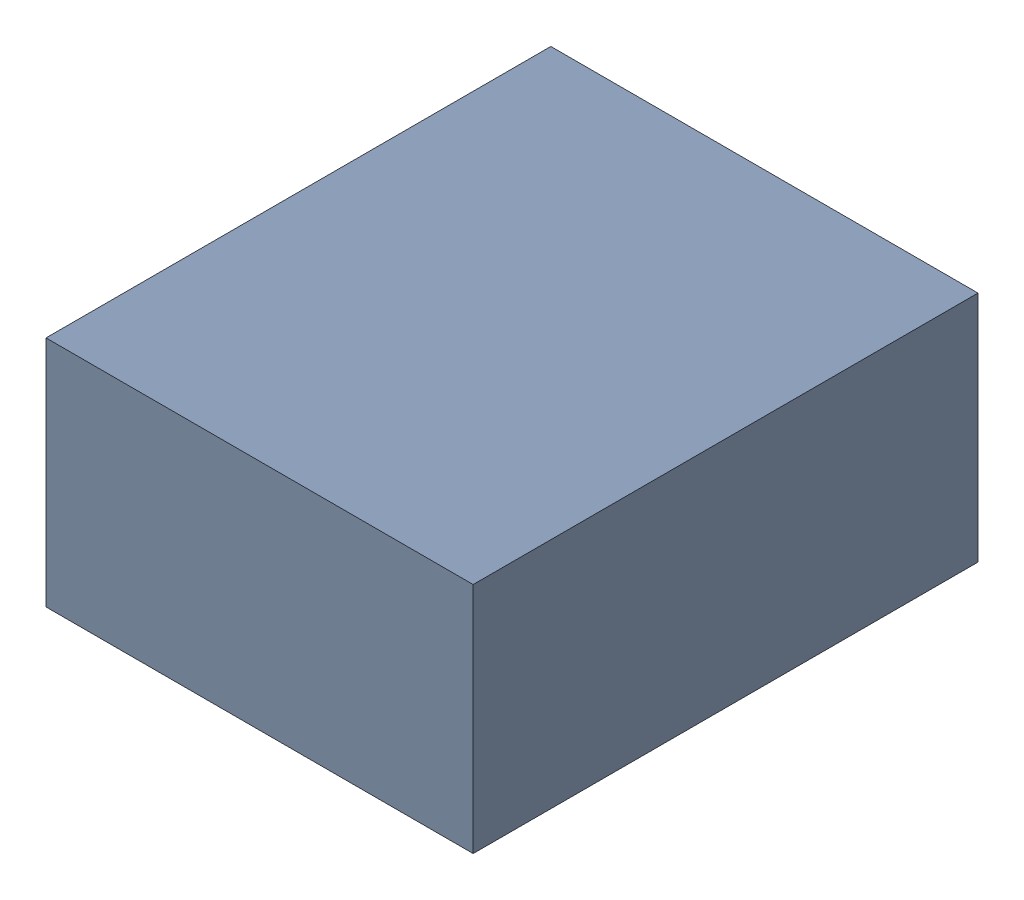
SolidWorks assembly C5, configuration Standard. Lengths in mm.
Overall size (1.1 0.6 1.3).
2 component instances, 1 part files, 0 mates.
Components (placement in the parent):
- 885542240-1: 885542240 [Standard] at (-17.8 -0.7 0) size (1.1 0.6 1.3)
  - Extruded_28-1: Extruded_28 [Standard] at origin size (1.1 0.6 1.3)
